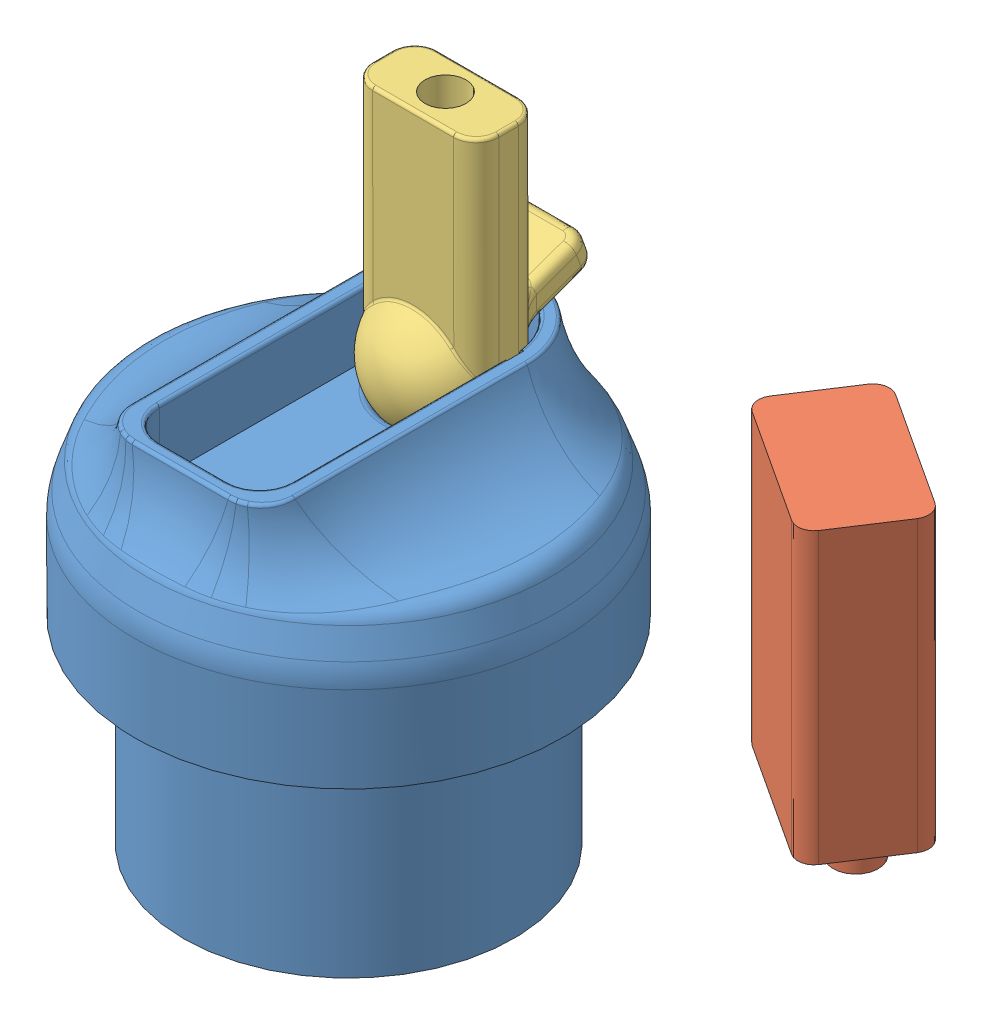
SolidWorks assembly Prototype_2 Assy, configuration Default. Lengths in mm.
Overall size (79.18 97.57 92.35).
5 component instances, 4 part files, 5 mates.
Components (placement in the parent):
- HF_Cap-1: HF_Cap [Default] at (-0.5256 -4.7804 39.9443) size (66 63.57 66)
- 9V-1: 9V [Default] at (30.3963 8.9696 -5.5984) x (-0.837169 0 -0.546944) z (-0.546944 0 0.837169) size (26 48.8 16)
- Cap insert-1: Cap insert [Default] at (-0.5256 22.7196 24.9443) x (1 0 0) z (0 -0.999999 -0.001046) size (22.3 26.32 44.48)
- Flowmeter Assy-1: Flowmeter Assy [Default] at (-3.542 -1.2442 49.2802) x (-0.029812 0 0.999556) z (0 -1 0) size (25.4 19.05 45.4)
  - Flowmeter Mockup-1: Flowmeter Mockup [Default] at (-16.715 -11.8145 8.2187) size (25.4 19.05 45.4)
Mates (geometry in assembly coordinates):
- Coincident1: coincident anti-aligned: plane of HF_Cap-1 through (-0.5256 8.9696 39.9443) normal (0 -1 0); plane of 9V-1 through (24.6142 8.9696 -15.9458) normal (0 1 0)
- Concentric3: concentric aligned: circle of HF_Cap-1; circle of Cap insert-1
- Concentric7: concentric aligned: circle of HF_Cap-1; circle of Cap insert-1
- Distance3: distance = 0.1 mm anti-aligned: plane of Cap insert-1 through (10.6244 22.7196 24.9443) normal (1 0 0); plane of HF_Cap-1 through (10.7244 22.7196 24.9443) normal (-1 0 0)
- Coincident5: coincident anti-aligned: circle of HF_Cap-1; circle of Flowmeter Assy-1/Flowmeter Mockup-1
